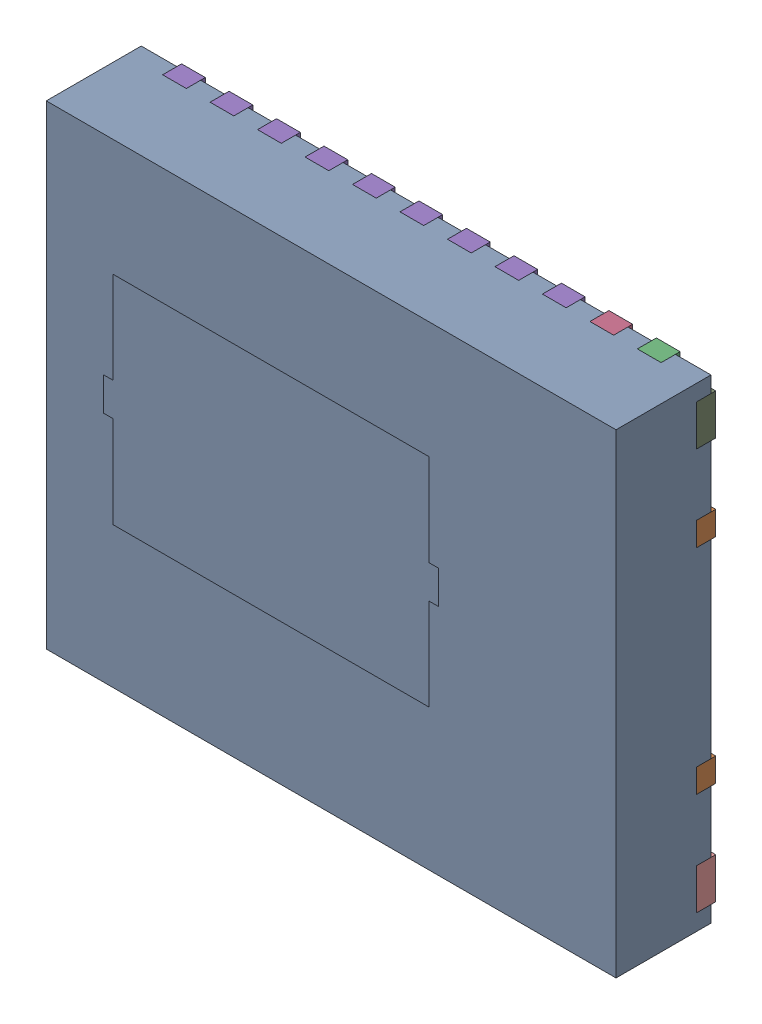
SolidWorks assembly U3, configuration Default. Lengths in mm.
Overall size (6 5 1.05).
15 component instances, 13 part files, 0 mates.
Components (placement in the parent):
- DMM0022A-1: DMM0022A [Default] at (27.9401 42.5449 0) x (0 -1 0) z (0 0 1) size (5 6 1.05)
  - BODY-SON-1: BODY-SON [Default] at (0 0 0.05) x (1 0 0) z (0 -1 0) size (5 1 6)
  - FRAME-DMM0022A-1: FRAME-DMM0022A [Default] x (1 0 0) z (0 -1 0) size (5 0.2 6)
    - Open CASCADE STEP translator 7.5 1.2.1.2.1-1: Open CASCADE STEP translator 7.5 1.2.1.2.1 [Default] at origin size (3.5 0.2 6)
    - Open CASCADE STEP translator 7.5 1.2.1.2.2-1: Open CASCADE STEP translator 7.5 1.2.1.2.2 [Default] at origin size (0.5 0.2 0.25)
    - Open CASCADE STEP translator 7.5 1.2.1.2.3-1: Open CASCADE STEP translator 7.5 1.2.1.2.3 [Default] at origin size (0.5 0.2 0.25)
    - Open CASCADE STEP translator 7.5 1.2.1.2.4-1: Open CASCADE STEP translator 7.5 1.2.1.2.4 [Default] at origin size (0.5 0.2 4.25)
    - Open CASCADE STEP translator 7.5 1.2.1.2.5-1: Open CASCADE STEP translator 7.5 1.2.1.2.5 [Default] at origin size (0.5 0.2 0.25)
    - Open CASCADE STEP translator 7.5 1.2.1.2.6-1: Open CASCADE STEP translator 7.5 1.2.1.2.6 [Default] at origin size (0.5 0.2 0.25)
    - Open CASCADE STEP translator 7.5 1.2.1.2.7-1: Open CASCADE STEP translator 7.5 1.2.1.2.7 [Default] at origin size (0.5 0.2 4.25)
    - Open CASCADE STEP translator 7.5 1.2.1.2.8-1: Open CASCADE STEP translator 7.5 1.2.1.2.8 [Default] at origin size (0.43 0.2 0.18)
    - Open CASCADE STEP translator 7.5 1.2.1.2.9-1: Open CASCADE STEP translator 7.5 1.2.1.2.9 [Default] at origin size (0.43 0.2 0.18)
    - Open CASCADE STEP translator 7.5 1.2.1.2.10-1: Open CASCADE STEP translator 7.5 1.2.1.2.10 [Default] at origin size (0.43 0.2 0.18)
    - Open CASCADE STEP translator 7.5 1.2.1.2.11-1: Open CASCADE STEP translator 7.5 1.2.1.2.11 [Default] at origin size (0.43 0.2 0.18)
  - HEATSLUG-1: HEATSLUG [Default] at (-0.128 -0.635 0.958) x (1 0 0) z (0 -1 0) size (2.28 0.09 3.53)
